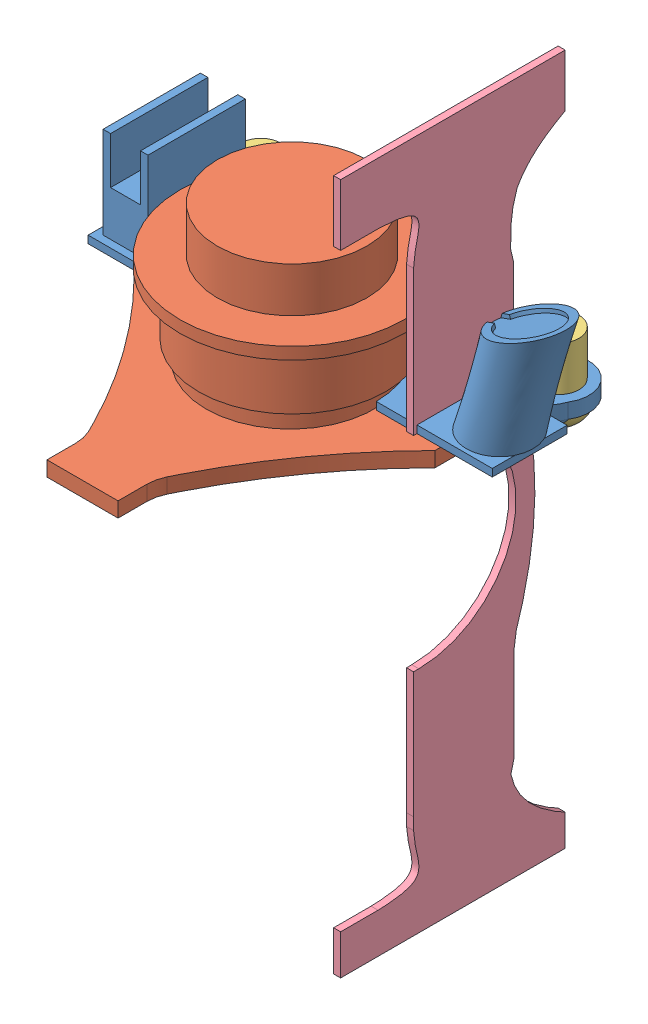
SolidWorks assembly wheel assembly v2, configuration Default. Lengths in mm.
Overall size (150.6 234.62 121.29).
5 component instances, 4 part files, 11 mates.
Components (placement in the parent):
- Paddle Enclosure V3-1: Paddle Enclosure V3 [Default] at origin size (150.6 52.82 50.8)
- steering_wheel-1: steering_wheel [Default] at (0 -5.08 -0.635) size (102.11 51.05 111.76)
- button-1: button [Default] at (-50.5888 -5.334 -40.64) x (-1 0 0) z (0 0 1) size (17.5 27.2 17.5)
- Paddles-1: Paddles [Default] at (0 2.54 13.2093) x (-1 0 0) z (0 -1 0) size (2.4 76.21 234.62)
- button-2: button [Default] at (50.5888 -5.334 -40.64) x (-1 0 0) z (0 0 1) size (17.5 27.2 17.5)
Mates (geometry in assembly coordinates):
- Parallel1: parallel aligned: plane of Paddle Enclosure V3-1 through (-68.58 2.54 0) normal (-1 0 0); plane of steering_wheel-1 through (-51.054 0 -0.635) normal (-1 0 0)
- Coincident3: coincident anti-aligned: plane of Paddle Enclosure V3-1 through (0 0 0) normal (0 -1 0); plane of steering_wheel-1 through (0 0 -0.635) normal (0 1 0)
- Coincident5: coincident anti-aligned: plane of Paddle Enclosure V3-1 through (0 -0.254 -34.5313) normal (0 0 -1); plane of button-1 through (-53.5635 14.859 -34.5313) normal (0 0 1)
- Coincident6: coincident anti-aligned: circle of Paddle Enclosure V3-1; circle of button-1
- Concentric2: concentric anti-aligned: circle of Paddle Enclosure V3-1; circle of steering_wheel-1
- Concentric3: concentric: circle of steering_wheel-1; circle of Paddles-1
- Coincident7: coincident: plane of Paddle Enclosure V3-1 through (0 2.54 0) normal (0 1 0); plane of Paddles-1 through (43.18 2.54 -50.2907) normal (0 -1 0)
- Parallel3: parallel: plane of Paddle Enclosure V3-1 through (-66.04 17.78 0) normal (-1 0 0); plane of Paddles-1 through (-82.3919 61.7274 -50.2907) normal (-0.906308 0.422618 0)
- Coincident9: coincident anti-aligned: plane of Paddle Enclosure V3-1 through (0 -0.254 -34.5313) normal (0 0 -1); plane of button-2 through (47.6141 14.859 -34.5313) normal (0 0 1)
- Coincident10: coincident anti-aligned: circle of Paddle Enclosure V3-1; circle of button-2
- Parallel4: parallel: plane of Paddle Enclosure V3-1 through (68.58 2.54 -25.4) normal (1 0 0); plane of Paddles-1 through (43.18 2.54 -50.2907) normal (1 0 0)
